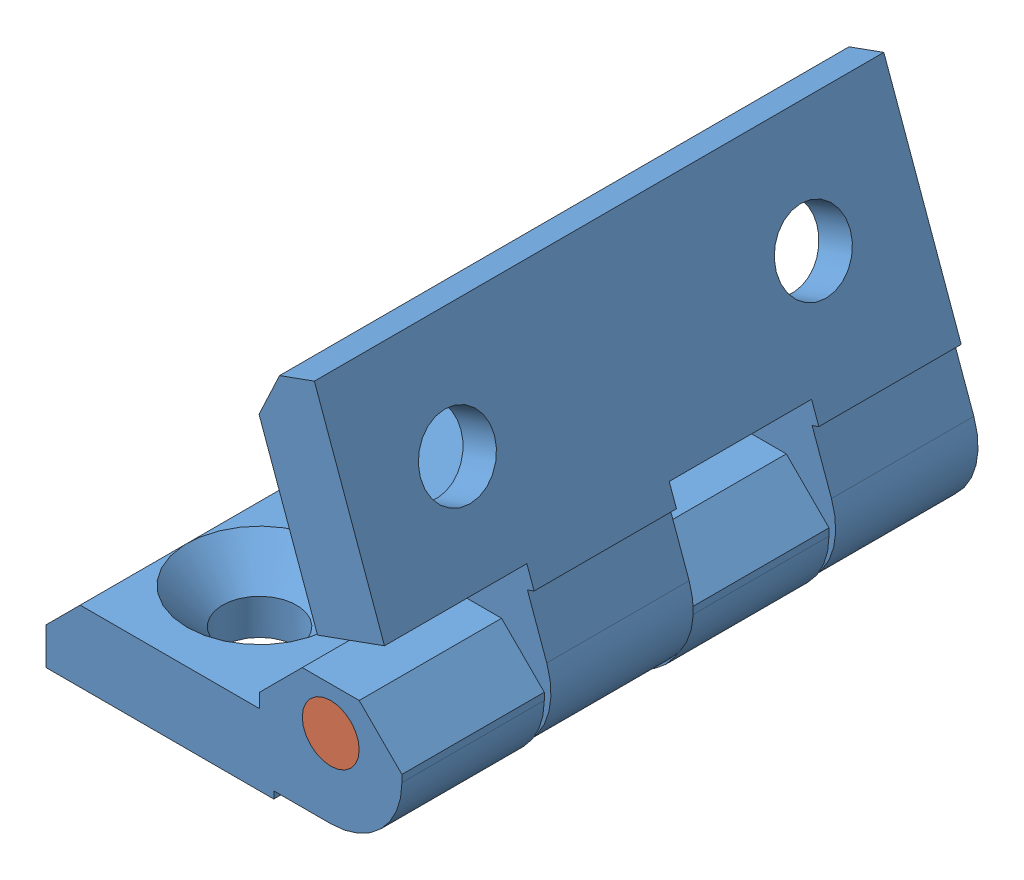
SolidWorks assembly 8020-12093-$PARTNUMBER, configuration Default. Lengths in mm.
Overall size (27.34 26.85 40).
3 component instances, 2 part files, 3 mates.
Components (placement in the parent):
- 8020-12093-$PARTNUMBER_1209308-1: 8020-12093-$PARTNUMBER_1209308 [Default] at (30.5586 23.0699 -35.9534) size (25 9 40)
- 8020-12093-$PARTNUMBER_1209308-2: 8020-12093-$PARTNUMBER_1209308 [Default] at (19.2215 6.9227 4.0466) x (0.339628 -0.94056 0) z (0 0 -1) size (25 9 40)
- 8020-12093-$PARTNUMBER_1209301-1: 8020-12093-$PARTNUMBER_1209301 [Default] at (13.5833 19.0732 -15.9534) x (1 0 0) z (0 1 0) size (4 40 4)
Mates (geometry in assembly coordinates):
- Hinge1: hinge aligned: cylinder of 8020-12093-$PARTNUMBER_1209308-2 through (19.0833 19.0732 -35.9534) axis (0 0 1) radius 2; cylinder of 8020-12093-$PARTNUMBER_1209308-1 through (19.0833 19.0732 4.0466) axis (0 0 -1) radius 2; plane of 8020-12093-$PARTNUMBER_1209308-1 through (19.0833 18.5732 -35.9534) normal (0 0 -1); plane of 8020-12093-$PARTNUMBER_1209308-2 through (19.5536 19.243 -35.9534) normal (0 0 -1)
- Concentric1: concentric aligned: cylinder of 8020-12093-$PARTNUMBER_1209308-2 through (19.0833 19.0732 -35.9534) axis (0 0 1) radius 2; cylinder of 8020-12093-$PARTNUMBER_1209301-1 through (19.0833 19.0732 -15.9534) axis (0 0 1) radius 2
- Coincident1: coincident aligned: plane of 8020-12093-$PARTNUMBER_1209308-2 through (19.5536 19.243 -35.9534) normal (0 0 -1); plane of 8020-12093-$PARTNUMBER_1209301-1 through (20.0833 19.0732 -35.9534) normal (0 0 -1)
